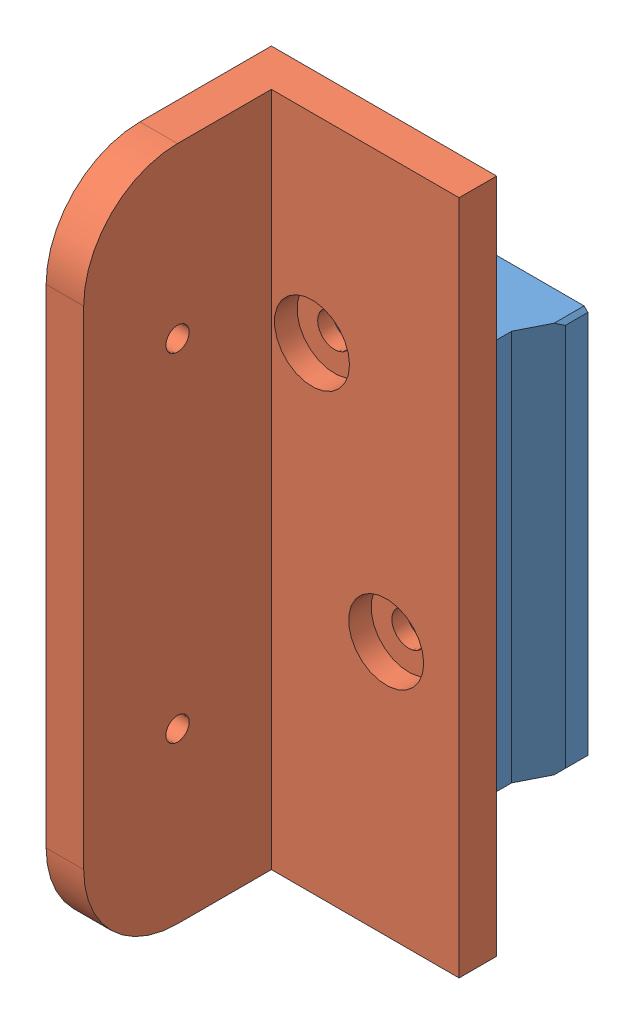
SolidWorks assembly Support_ass, configuration Défaut. Lengths in mm.
Overall size (42.3 90 39.75).
2 component instances, 2 part files, 3 mates.
Components (placement in the parent):
- support mannfrotto-1: support mannfrotto [Défaut] at (-7.6014 -1.604 52.1) size (42.3 52.1 9.75)
- support camera-1: support camera [Défaut] at (-7.6014 -1.704 52.1) size (30 90 30)
Mates (geometry in assembly coordinates):
- Coïncidente1: coincident anti-aligned: plane of support mannfrotto-1 through (-26.3514 24.446 61.85) normal (0 0 1); plane of support camera-1 through (-7.6014 -1.704 61.85) normal (0 0 -1)
- Coïncidente2: coincident aligned: plane of support mannfrotto-1 through (11.1486 24.446 61.85) normal (1 0 0); plane of support camera-1 through (11.1486 24.346 61.85) normal (1 0 0)
- Distance1: distance = 19 mm aligned: plane of support camera-1 through (11.1486 -46.654 66.85) normal (0 -1 0); plane of support mannfrotto-1 through (-7.6014 -27.654 56.7477) normal (0 -1 0)
